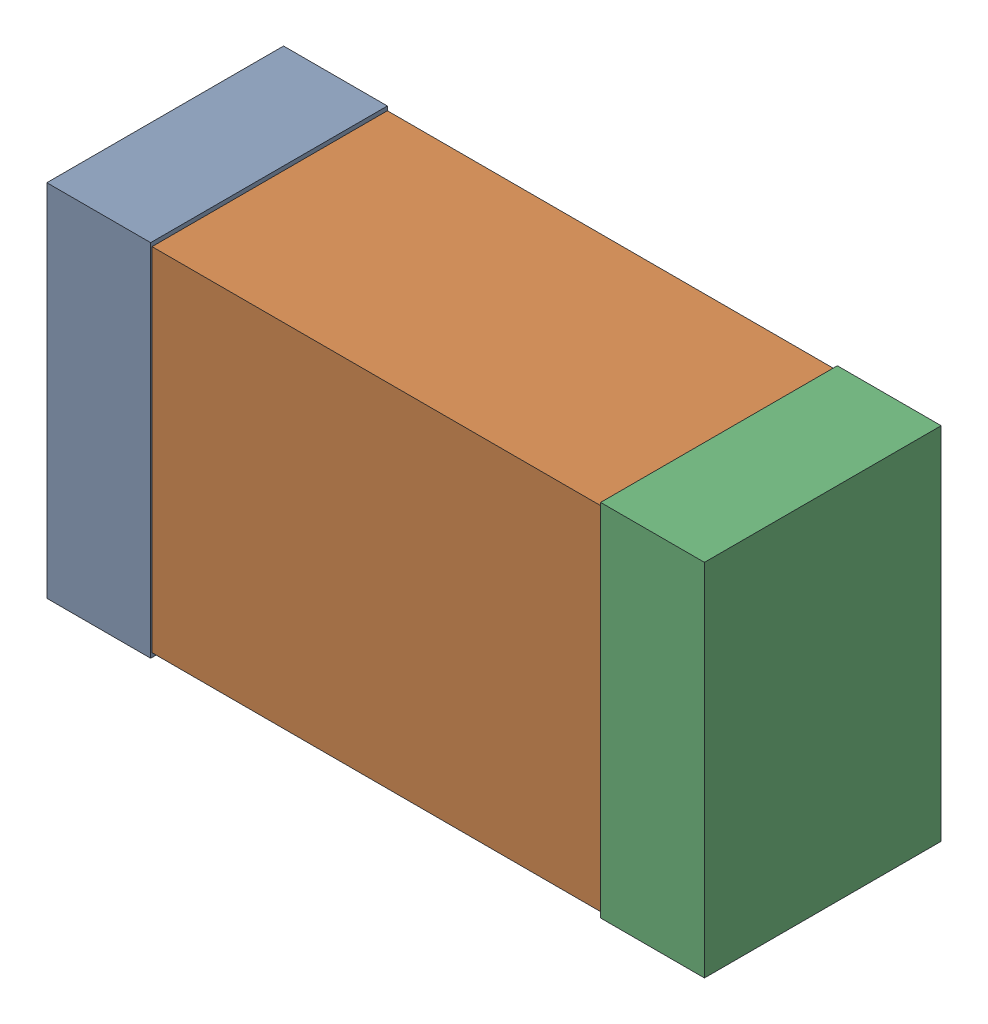
SolidWorks assembly C13_Motor_1Kanaloa_v2.0.0_Motor, configuration Default. Lengths in mm.
Overall size (2.38 1.3 0.85).
6 component instances, 2 part files, 0 mates.
Components (placement in the parent):
- 352877648-1: 352877648 [Default] at (102.378 59.69 0) size (0.38 1.3 0.85)
  - Extruded_14-1: Extruded_14 [Default] at origin size (0.38 1.3 0.85)
- 352877392-1: 352877392 [Default] at (103.378 59.69 0) size (2.2 1.27 0.85)
  - Extruded_15-1: Extruded_15 [Default] at origin size (2.2 1.27 0.85)
- 352877648-2: 352877648 [Default] at (104.378 59.69 0) size (0.38 1.3 0.85)
  - Extruded_14-1: Extruded_14 [Default] at origin size (0.38 1.3 0.85)
